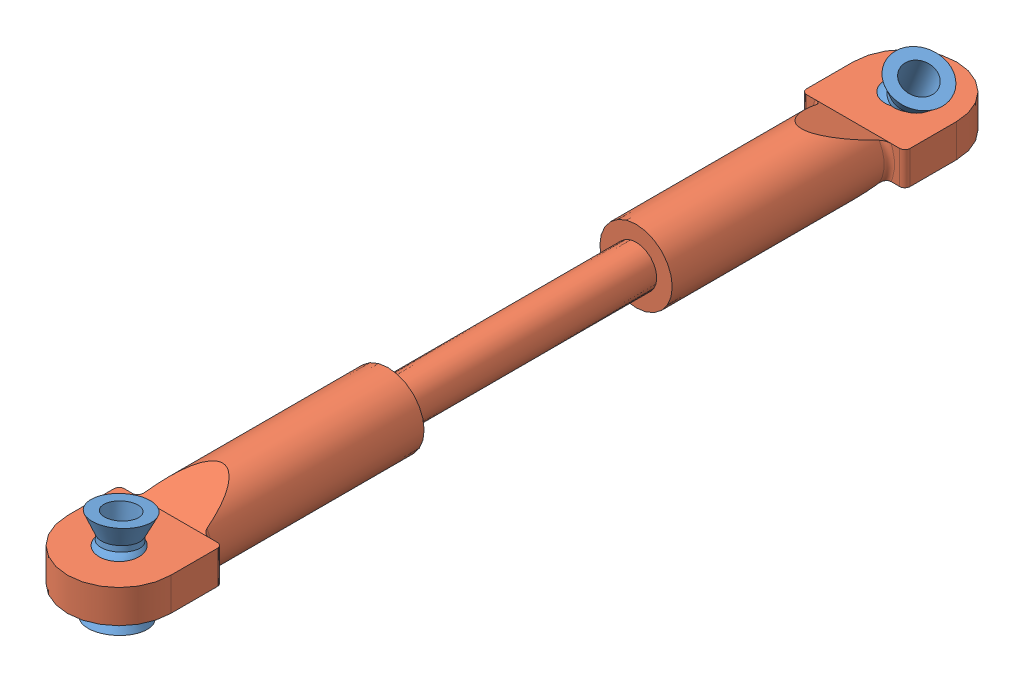
SolidWorks assembly TurnbuckleAssy_Rear, configuration Default. Lengths in mm.
Overall size (10 9.69 86).
3 component instances, 2 part files, 2 mates.
Components (placement in the parent):
- Turnbuckle Ball Spacer-1: Turnbuckle Ball Spacer [Default] at (-25.0236 -4.6638 -11.5869) x (0.416171 0.905102 0.087129) z (-0.208661 0.001798 0.977986) size (8.25 5.2 5.2)
- Turnbuckle Bar_REAR-1: Turnbuckle Bar_REAR [Default] at (-25.0236 -4.6638 26.4131) size (10 7 86)
- Turnbuckle Ball Spacer-2: Turnbuckle Ball Spacer [Default] at (-25.0236 -4.6638 64.4131) x (-0.072069 0.990072 -0.120675) z (-0.090577 0.113993 0.989344) size (8.25 5.2 5.2)
Mates (geometry in assembly coordinates):
- Coincident1: coincident: point of Turnbuckle Ball Spacer-1; point of Turnbuckle Bar_REAR-1
- Coincident2: coincident: point of Turnbuckle Bar_REAR-1; point of Turnbuckle Ball Spacer-2
